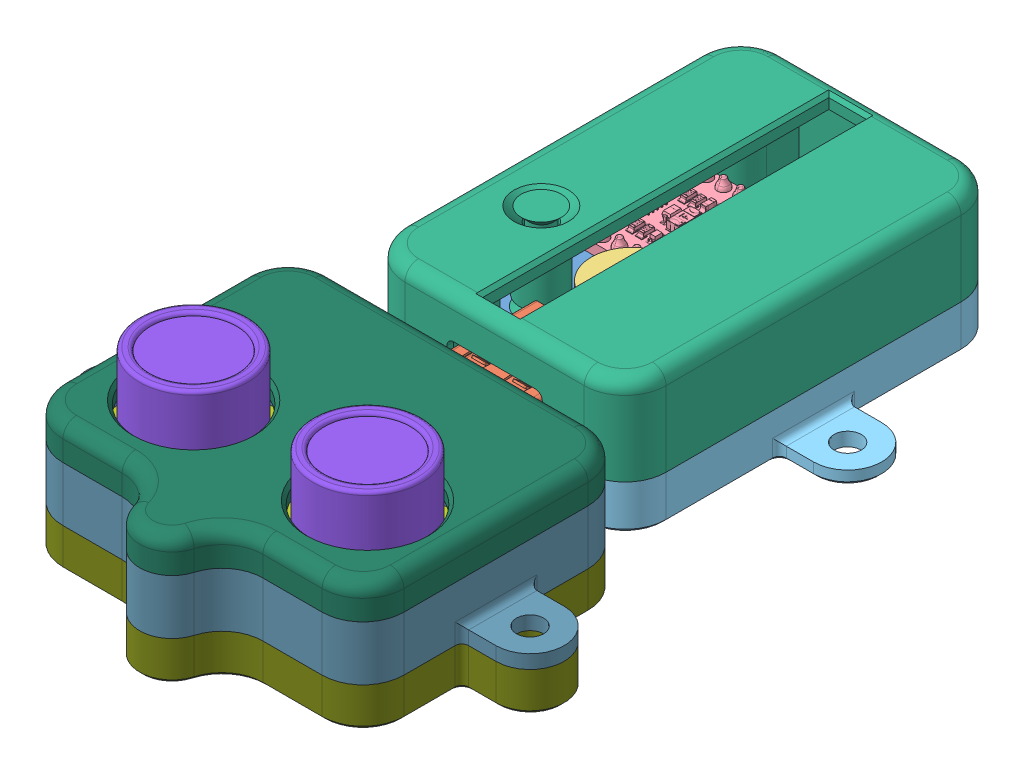
SolidWorks assembly ParkingPal, configuration Default. Lengths in mm.
Overall size (70 25.52 107.27).
27 component instances, 16 part files, 6 mates.
Components (placement in the parent):
- MCU_assem-1: MCU_assem [Default] at (17.7762 30.515 46.7785) size (58.29 19.5 56.77)
  - MCU_pcb-1: MCU_pcb [Default] at (2.7151 19.0352 49.2946) size (34.29 3.22 48.26)
  - USB-A-1: USB-A [Default] at (19.8234 27.5552 41.9997) x (1 0 0) z (0 1 0) size (15.09 13.8 10.75)
  - Buzzer-1: Buzzer [Default] at (19.8234 20.6552 34.0546) size (12 8.5 12)
  - ARDUINO PRO MICRO-1: ARDUINO PRO MICRO [Default] at (6.5251 21.9252 25.1746) size (34.59 4.25 17.78)
  - Case_bottom-1: Case_bottom [Default] at (2.7151 19.0352 49.2946) x (-1 0 0) z (0 -1 0) size (58.29 55.26 8)
  - Case_top-1: Case_top [Default] at (2.7151 21.5352 49.2946) x (1 0 0) z (0 1 0) size (38.29 55.26 13.75)
- SMU_assem-1: SMU_assem [Default] at (20.7789 35.2649 92.2464) size (70 19.75 60.58)
  - HC-SR04 Ping Sensor-2: HC-SR04 Ping Sensor [Default] at (16.8208 22.0579 40.5842) x (0 0 -1) z (0 1 0) size (25.18 45 18.07)
    - PCB-1: PCB [Default] at origin size (20.5 45 1.75)
    - Transducer-1: Transducer [Default] at (0 -13.16 13.25) x (1 0 0) z (0 -1 0) size (15.88 12 15.88)
    - Transducer-2: Transducer [Default] at (0 12.34 13.25) x (1 0 0) z (0 -1 0) size (15.88 12 15.88)
    - 3 Pin Header 90 Degree-1: 3 Pin Header 90 Degree [Default] at (8.4275 0 -1.25) x (-1 0 0) z (0 -1 0) size (8 7.82 10)
    - 14 Pin SMT-1: 14 Pin SMT [Default] at (-0.35 -18.5 -0.85) x (0 -1 0) z (1 0 0) size (6 1.6 8.8)
    - 14 Pin SMT-2: 14 Pin SMT [Default] at (0 -0.3826 -0.85) x (1 0 0) z (0 1 0) size (6 1.6 8.8)
    - 14 Pin SMT-3: 14 Pin SMT [Default] at (0 17.5274 -0.85) x (1 0 0) z (0 1 0) size (6 1.6 8.8)
    - Cap1 SMT-1: Cap1 SMT [Default] at (-1.755 7.4774 -0.9689) x (0 1 0) z (-1 0 0) size (4.5 1.84 1.75)
    - Cap1 SMT-2: Cap1 SMT [Default] at (6.835 7.4774 -0.9689) x (0 1 0) z (-1 0 0) size (4.5 1.84 1.75)
    - Cap1 SMT-3: Cap1 SMT [Default] at (-6.835 7.4774 -0.9689) x (0 1 0) z (-1 0 0) size (4.5 1.84 1.75)
    - Cap1 SMT-4: Cap1 SMT [Default] at (4.295 7.4774 -0.9689) x (0 1 0) z (-1 0 0) size (4.5 1.84 1.75)
    - Cap1 SMT-5: Cap1 SMT [Default] at (1.755 7.4774 -0.9689) x (0 1 0) z (-1 0 0) size (4.5 1.84 1.75)
    - Cap1 SMT-6: Cap1 SMT [Default] at (-4.295 7.4774 -0.9689) x (0 1 0) z (-1 0 0) size (4.5 1.84 1.75)
    - HC-SR04 Crystal-1: HC-SR04 Crystal [Default] at (-8.3 0 1.75) x (0 -1 0) z (0 0 1) size (10 3.5 2.7)
  - SMU_pcb-1: SMU_pcb [Default] at (16.8208 18.3753 0.2567) x (0 0 1) z (-1 0 0) size (30.4 1.62 14.45)
  - SMU_case_bottom-2: SMU_case_bottom [Default] at (16.8208 16.0579 14.0842) x (1 0 0) z (0 1 0) size (70 46.75 8)
  - SMU_case_top-1: SMU_case_top [Default] at (16.8208 24.0579 14.0842) x (1 0 0) z (0 1 0) size (50 46.75 9)
- SMU_spacer-1: SMU_spacer [Default] at (37.5996 51.3228 106.3306) x (-1 0 0) z (0 -1 0) size (70 46.75 5.75)
Mates (geometry in assembly coordinates):
- Coincident1: coincident: plane of MCU_assem-1/USB-A-1 through (37.5996 58.0702 88.7782) normal (1 0 0); plane of SMU_assem-1/SMU_pcb-1 through (37.5996 53.6402 92.5031) normal (-1 0 0)
- Coincident2: coincident: plane of MCU_assem-1/USB-A-1 through (32.0496 55.2602 93.2582) normal (0 -1 0); plane of SMU_assem-1/SMU_pcb-1 through (37.5996 55.2602 92.5031) normal (0 1 0)
- InPlace1: in place: plane of SMU_assem-1/SMU_case_bottom-2 through (37.5996 51.3228 106.3306) normal (0 -1 0); plane of ? through (0 51.3228 0) normal (0 -1 0); moOrthogonalPlaneRef_w of SMU_assem-1/SMU_case_bottom-2 through (37.5996 51.3228 106.3306) normal (0 -1 0); plane of ? through (0 51.3228 0) normal (0 0 -1); plane of SMU_assem-1/SMU_case_bottom-2 through (37.5996 51.3228 106.3306) normal (0 -1 0); plane of ? through (0 51.3228 0) normal (-1 0 0); plane of SMU_assem-1/SMU_case_bottom-2 through (37.5996 51.3228 106.3306) normal (0 -1 0); unknown of SMU_spacer-1
- Coincident3: coincident: plane of SMU_assem-1/SMU_case_bottom-2; plane of SMU_spacer-1
- Coincident4: coincident: moOrthogonalPlaneRef_w of SMU_assem-1/SMU_case_bottom-2 through (37.5996 51.3228 106.3306) normal (0 0 -1); plane of SMU_spacer-1 through (37.5996 51.3228 106.3306) normal (0 0 -1)
- Coincident5: coincident: moOrthogonalPlaneRef_w of SMU_assem-1/SMU_case_bottom-2 through (37.5996 51.3228 106.3306) normal (1 0 0); plane of SMU_spacer-1 through (37.5996 51.3228 106.3306) normal (-1 0 0)
